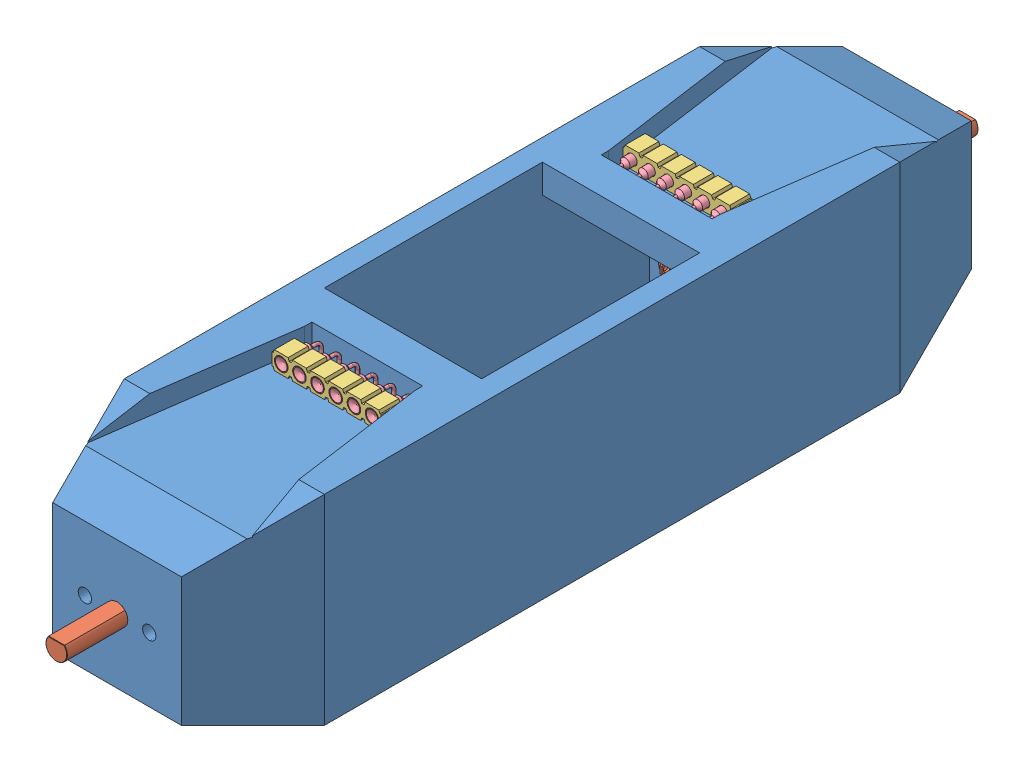
SolidWorks assembly Module_Motor, configuration Default. Lengths in mm.
Overall size (28 28 127.5).
19 component instances, 4 part files, 14 mates.
Components (placement in the parent):
- Module - RB_Gears-1: Module - RB_Gears [Motor] at (37.8746 66.7149 80.4494) size (28 28 110.5)
- micro-metal-gearmotor-1000-backshaft-1: micro-metal-gearmotor-1000-backshaft [Default] at (37.8746 66.7149 39.1994) x (-1 0 0) z (0 0 -1) size (12.01 10.08 43.7)
- micro-metal-gearmotor-1000-backshaft-2: micro-metal-gearmotor-1000-backshaft [Default] at (37.8746 66.7149 121.6994) size (12.01 10.08 43.7)
- mill-max-399-10-106-10-007000-1: mill-max-399-10-106-10-007000 [Default] at (87.4391 79.2849 107.5811) x (1 0 0) z (0 -1 0) size (15.24 5.81 5.74)
  - mill-max-399-10-106-10-007000_P3XX-11-010-00-000000(P306-11-010-00-000000)-1: mill-max-399-10-106-10-007000_P3XX-11-010-00-000000(P306-11-010-00-000000) [Default] at (-56.7488 -1.0694 1.27) size (15.24 2.79 2.54)
  - mill-max-399-10-106-10-007000_1960(1960-0-00-15-00-00-03-0)-1: mill-max-399-10-106-10-007000_1960(1960-0-00-15-00-00-03-0) [Default] at (-50.7044 -1.0694 0) x (0 -1 0) z (1 0 0) size (5.81 5.38 1.83)
  - mill-max-399-10-106-10-007000_1960(1960-0-00-15-00-00-03-0)-2: mill-max-399-10-106-10-007000_1960(1960-0-00-15-00-00-03-0) [Default] at (-43.0844 -1.0694 0) x (0 -1 0) z (1 0 0) size (5.81 5.38 1.83)
  - mill-max-399-10-106-10-007000_1960(1960-0-00-15-00-00-03-0)-3: mill-max-399-10-106-10-007000_1960(1960-0-00-15-00-00-03-0) [Default] at (-55.7844 -1.0694 0) x (0 -1 0) z (1 0 0) size (5.81 5.38 1.83)
  - mill-max-399-10-106-10-007000_1960(1960-0-00-15-00-00-03-0)-4: mill-max-399-10-106-10-007000_1960(1960-0-00-15-00-00-03-0) [Default] at (-48.1644 -1.0694 0) x (0 -1 0) z (1 0 0) size (5.81 5.38 1.83)
  - mill-max-399-10-106-10-007000_1960(1960-0-00-15-00-00-03-0)-5: mill-max-399-10-106-10-007000_1960(1960-0-00-15-00-00-03-0) [Default] at (-53.2444 -1.0694 0) x (0 -1 0) z (1 0 0) size (5.81 5.38 1.83)
  - mill-max-399-10-106-10-007000_1960(1960-0-00-15-00-00-03-0)-6: mill-max-399-10-106-10-007000_1960(1960-0-00-15-00-00-03-0) [Default] at (-45.6244 -1.0694 0) x (0 -1 0) z (1 0 0) size (5.81 5.38 1.83)
- mill-max-399-10-106-10-007000-2: mill-max-399-10-106-10-007000 [Default] at (-11.6898 79.2849 53.3178) x (-1 0 0) z (0 -1 0) size (15.24 5.81 5.74)
  - mill-max-399-10-106-10-007000_P3XX-11-010-00-000000(P306-11-010-00-000000)-1: mill-max-399-10-106-10-007000_P3XX-11-010-00-000000(P306-11-010-00-000000) [Default] at (-56.7488 -1.0694 1.27) size (15.24 2.79 2.54)
  - mill-max-399-10-106-10-007000_1960(1960-0-00-15-00-00-03-0)-1: mill-max-399-10-106-10-007000_1960(1960-0-00-15-00-00-03-0) [Default] at (-50.7044 -1.0694 0) x (0 -1 0) z (1 0 0) size (5.81 5.38 1.83)
  - mill-max-399-10-106-10-007000_1960(1960-0-00-15-00-00-03-0)-2: mill-max-399-10-106-10-007000_1960(1960-0-00-15-00-00-03-0) [Default] at (-43.0844 -1.0694 0) x (0 -1 0) z (1 0 0) size (5.81 5.38 1.83)
  - mill-max-399-10-106-10-007000_1960(1960-0-00-15-00-00-03-0)-3: mill-max-399-10-106-10-007000_1960(1960-0-00-15-00-00-03-0) [Default] at (-55.7844 -1.0694 0) x (0 -1 0) z (1 0 0) size (5.81 5.38 1.83)
  - mill-max-399-10-106-10-007000_1960(1960-0-00-15-00-00-03-0)-4: mill-max-399-10-106-10-007000_1960(1960-0-00-15-00-00-03-0) [Default] at (-48.1644 -1.0694 0) x (0 -1 0) z (1 0 0) size (5.81 5.38 1.83)
  - mill-max-399-10-106-10-007000_1960(1960-0-00-15-00-00-03-0)-5: mill-max-399-10-106-10-007000_1960(1960-0-00-15-00-00-03-0) [Default] at (-53.2444 -1.0694 0) x (0 -1 0) z (1 0 0) size (5.81 5.38 1.83)
  - mill-max-399-10-106-10-007000_1960(1960-0-00-15-00-00-03-0)-6: mill-max-399-10-106-10-007000_1960(1960-0-00-15-00-00-03-0) [Default] at (-45.6244 -1.0694 0) x (0 -1 0) z (1 0 0) size (5.81 5.38 1.83)
Mates (geometry in assembly coordinates):
- Coincident1: coincident anti-aligned: plane of Module - RB_Gears-1 through (37.8746 66.7149 26.6994) normal (0 0 1); plane of micro-metal-gearmotor-1000-backshaft-1 through (43.8746 71.7149 26.6994) normal (0 0 -1)
- Coincident2: coincident anti-aligned: plane of Module - RB_Gears-1 through (37.8746 66.7149 134.1994) normal (0 0 -1); plane of micro-metal-gearmotor-1000-backshaft-2 through (31.8746 71.7149 134.1994) normal (0 0 1)
- Concentric1: concentric anti-aligned: cylinder of Module - RB_Gears-1 through (37.8746 66.7149 20.9568) axis (0 0 1) radius 1.5; cylinder of micro-metal-gearmotor-1000-backshaft-1 through (37.8746 66.7149 22.1994) axis (0 0 -1) radius 1.5
- Concentric2: concentric aligned: cylinder of Module - RB_Gears-1 through (42.3746 66.7149 20.9568) axis (0 0 1) radius 0.95; cylinder of micro-metal-gearmotor-1000-backshaft-1 through (42.3746 66.7149 27.0994) axis (0 0 1) radius 0.8
- Concentric3: concentric anti-aligned: cylinder of Module - RB_Gears-1 through (37.8746 66.7149 139.9421) axis (0 0 -1) radius 1.5; cylinder of micro-metal-gearmotor-1000-backshaft-2 through (37.8746 66.7149 138.6994) axis (0 0 1) radius 1.5
- Concentric4: concentric aligned: cylinder of Module - RB_Gears-1 through (42.3746 66.7149 139.9421) axis (0 0 -1) radius 0.95; cylinder of micro-metal-gearmotor-1000-backshaft-2 through (42.3746 66.7149 133.7994) axis (0 0 -1) radius 0.8
- Tangent1: tangent anti-aligned: plane of Module - RB_Gears-1 through (45.6246 78.0149 100.6994) normal (0 0 1); cylinder of mill-max-399-10-106-10-007000-1/mill-max-399-10-106-10-007000_1960(1960-0-00-15-00-00-03-0)-2 through (44.3546 84.5216 100.928) axis (0 1 0) radius 0.2286
- Tangent2: tangent anti-aligned: plane of Module - RB_Gears-1 through (45.6246 78.0149 100.6994) normal (0 0 1); cylinder of mill-max-399-10-106-10-007000-1/mill-max-399-10-106-10-007000_1960(1960-0-00-15-00-00-03-0)-3 through (31.6546 84.5216 100.928) axis (0 1 0) radius 0.2286
- Tangent3: tangent anti-aligned: plane of Module - RB_Gears-1 through (45.6246 78.0149 60.1994) normal (0 0 -1); cylinder of mill-max-399-10-106-10-007000-2/mill-max-399-10-106-10-007000_1960(1960-0-00-15-00-00-03-0)-2 through (31.3946 84.5216 59.9708) axis (0 1 0) radius 0.2286
- Tangent4: tangent anti-aligned: plane of Module - RB_Gears-1 through (45.6246 78.0149 60.1994) normal (0 0 -1); cylinder of mill-max-399-10-106-10-007000-2/mill-max-399-10-106-10-007000_1960(1960-0-00-15-00-00-03-0)-3 through (44.0946 84.5216 59.9708) axis (0 1 0) radius 0.2286
- Coincident3: coincident anti-aligned: plane of Module - RB_Gears-1 through (37.8746 78.0149 80.4494) normal (0 1 0); plane of mill-max-399-10-106-10-007000-2/mill-max-399-10-106-10-007000_P3XX-11-010-00-000000(P306-11-010-00-000000)-1 through (45.059 78.0149 57.1811) normal (0 -1 0)
- Coincident4: coincident anti-aligned: plane of Module - RB_Gears-1 through (37.8746 78.0149 80.4494) normal (0 1 0); plane of mill-max-399-10-106-10-007000-1/mill-max-399-10-106-10-007000_P3XX-11-010-00-000000(P306-11-010-00-000000)-1 through (30.6903 78.0149 103.7177) normal (0 -1 0)
- Coincident5: coincident anti-aligned: plane of Module - RB_Gears-1 through (45.6246 78.0149 120.6994) normal (-1 0 0); plane of mill-max-399-10-106-10-007000-1/mill-max-399-10-106-10-007000_P3XX-11-010-00-000000(P306-11-010-00-000000)-1 through (45.6246 80.1549 103.7177) normal (1 0 0)
- Coincident7: coincident anti-aligned: plane of Module - RB_Gears-1 through (30.1246 78.0149 40.1994) normal (1 0 0); plane of mill-max-399-10-106-10-007000-2/mill-max-399-10-106-10-007000_P3XX-11-010-00-000000(P306-11-010-00-000000)-1 through (30.1246 80.1549 57.1811) normal (-1 0 0)
